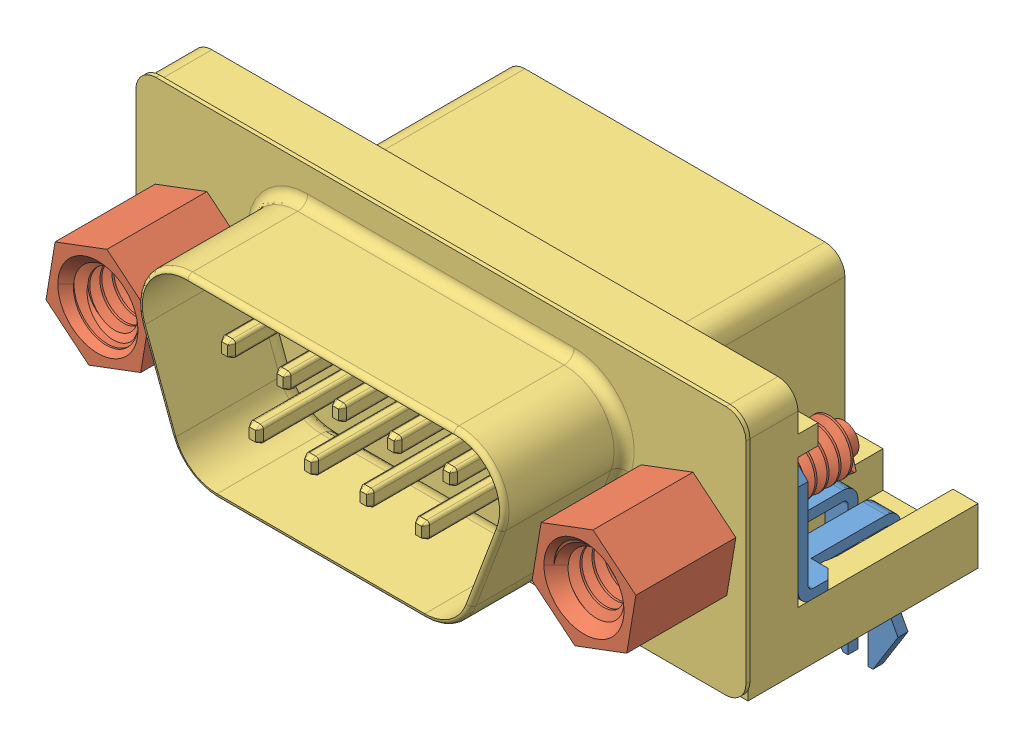
SolidWorks assembly ALSRobot-DB9-M, configuration Default. Lengths in mm.
Overall size (30.5 16.4 17.83).
5 component instances, 3 part files, 0 mates.
Components (placement in the parent):
- ALSRobot-DB9-M_User Library-DRB-9M_kont_1-1: ALSRobot-DB9-M_User Library-DRB-9M_kont_1 [Default] at (12.15 2.35 -2.95) x (1 0 0) z (0 1 0) size (6 6.5 12.5)
- ALSRobot-DB9-M_User Library-DRB-9M_kont_1-2: ALSRobot-DB9-M_User Library-DRB-9M_kont_1 [Default] at (-12.15 2.35 -2.95) x (1 0 0) z (0 1 0) size (6 6.5 12.5)
- ALSRobot-DB9-M_User Library-DRB-9M_st_1-1: ALSRobot-DB9-M_User Library-DRB-9M_st_1 [Default] at (-12.15 -0.15 0) x (-1 0 0) z (0 0 1) size (5.19 5.47 13)
- ALSRobot-DB9-M_User Library-DRB-9M_st_1-2: ALSRobot-DB9-M_User Library-DRB-9M_st_1 [Default] at (12.15 -0.15 0) size (5.19 5.47 13)
- ALSRobot-DB9-M_User Library-DRB-9M_DRB-9M_1-1: ALSRobot-DB9-M_User Library-DRB-9M_DRB-9M_1 [Default] at origin size (30.5 13.9 17.83)
